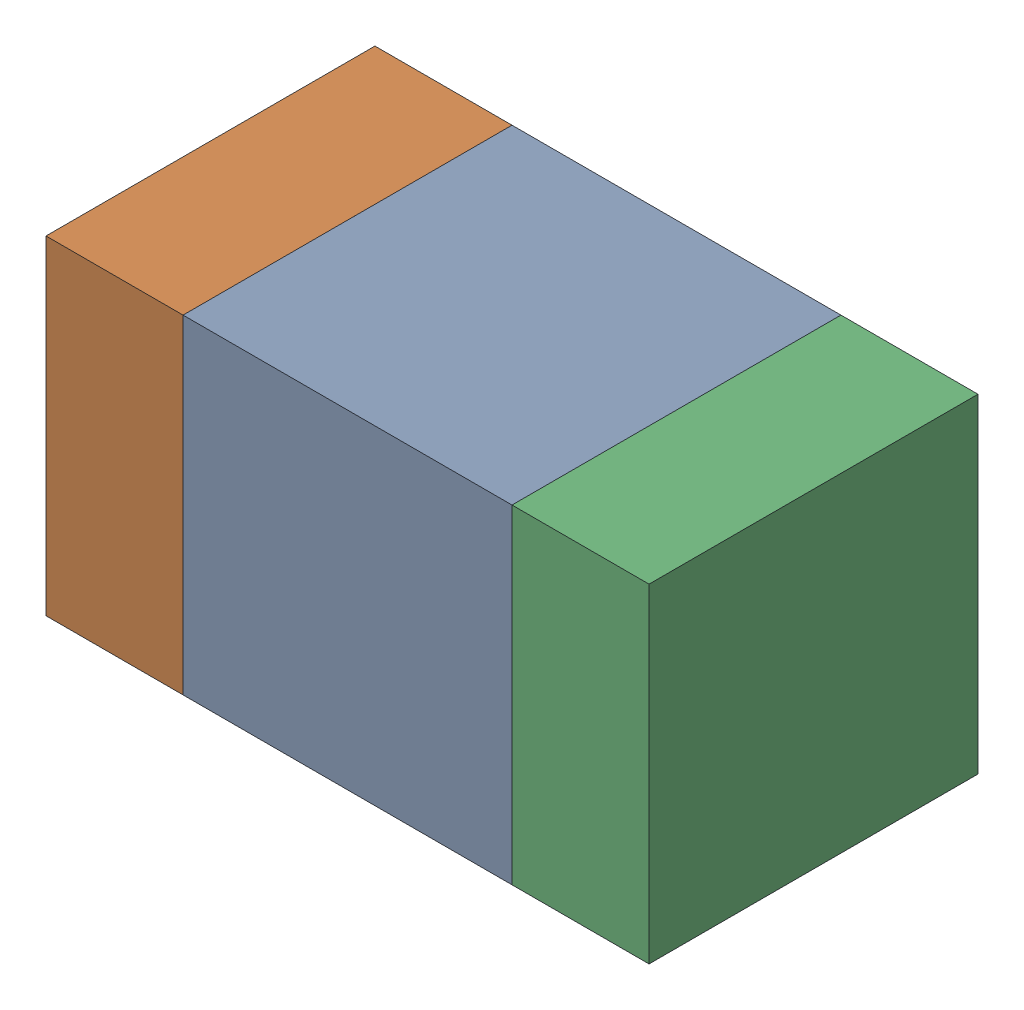
SolidWorks assembly C307_2PCB, configuration Default. Lengths in mm.
Overall size (1.1 0.6 0.6).
6 component instances, 2 part files, 0 mates.
Components (placement in the parent):
- 761606048-1: 761606048 [Default] at (130.6 98.5 0) size (0.6 0.6 0.6)
  - Extruded_9-1: Extruded_9 [Default] at origin size (0.6 0.6 0.6)
- 854785160-1: 854785160 [Default] at (130.175 98.5 0) size (0.25 0.6 0.6)
  - Extruded_19-1: Extruded_19 [Default] at origin size (0.25 0.6 0.6)
- 854785160-2: 854785160 [Default] at (131.025 98.5 0) size (0.25 0.6 0.6)
  - Extruded_19-1: Extruded_19 [Default] at origin size (0.25 0.6 0.6)
